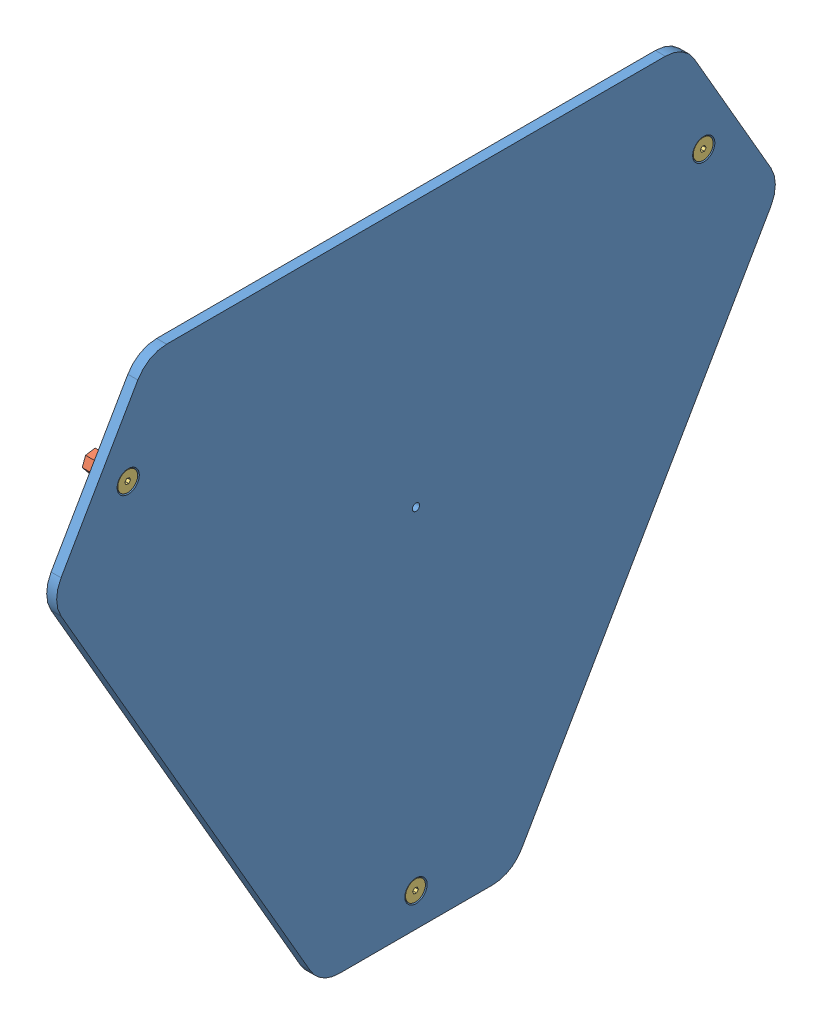
SolidWorks assembly Heat_Bed, configuration Défaut. Lengths in mm.
Overall size (11 282.32 272.69).
7 component instances, 3 part files, 4 mates.
Components (placement in the parent):
- Bed_v2.1-1: Bed_v2.1 [Défaut] at (14.4627 117.7414 58.9942) x (0 -0.866025 -0.5) z (1 0 0) size (216.3 190 3)
- Entretoise-1: Entretoise [Défaut] at (14.4627 17.7414 58.9942) x (0 -0.35374 -0.935344) z (-1 0 0) size (5 5.77 8)
- TFHC_M3-1: TFHC_M3 [M3x8] at (17.3027 17.7414 58.9942) x (-1 0 0) z (0 -0.924225 -0.381849) size (9.7 6 6)
- TFHC_M3-2: TFHC_M3 [M3x8] at (17.3027 167.7414 -27.6083) x (-1 0 0) z (0 0.792804 -0.609477) size (9.7 6 6)
- TFHC_M3-3: TFHC_M3 [M3x8] at (17.3027 167.7414 145.5968) x (-1 0 0) z (0 0.131421 0.991327) size (9.7 6 6)
- Entretoise-2: Entretoise [Défaut] at (14.4627 167.7414 -27.6083) x (0 0.986902 0.161324) z (-1 0 0) size (5 5.77 8)
- Entretoise-3: Entretoise [Défaut] at (14.4627 167.7414 145.5968) x (0 -0.633161 0.77402) z (-1 0 0) size (5 5.77 8)
Mates (geometry in assembly coordinates):
- Coaxiale4: concentric aligned: cylinder of Bed_v2.1-1 through (17.4627 17.7414 58.9942) axis (1 0 0) radius 1.7; cylinder of TFHC_M3-1 through (17.3027 17.7414 58.9942) axis (1 0 0) radius 1.5
- Coïncidente20: coincident aligned: cone of Bed_v2.1-1 through (17.4627 17.7414 58.9942) axis (-1 0 0); cone of TFHC_M3-1 through (15.6027 17.7414 58.9942) axis (-1 0 0)
- Coaxiale5: concentric anti-aligned: cylinder of Entretoise-1 through (6.4627 17.7414 58.9942) axis (-1 0 0) radius 1.25; cylinder of TFHC_M3-1 through (17.3027 17.7414 58.9942) axis (1 0 0) radius 1.5
- Coïncidente21: coincident anti-aligned: plane of Entretoise-1 through (14.4627 17.7414 58.9942) normal (1 0 0); plane of Bed_v2.1-1 through (14.4627 187.7414 134.0498) normal (-1 0 0)
